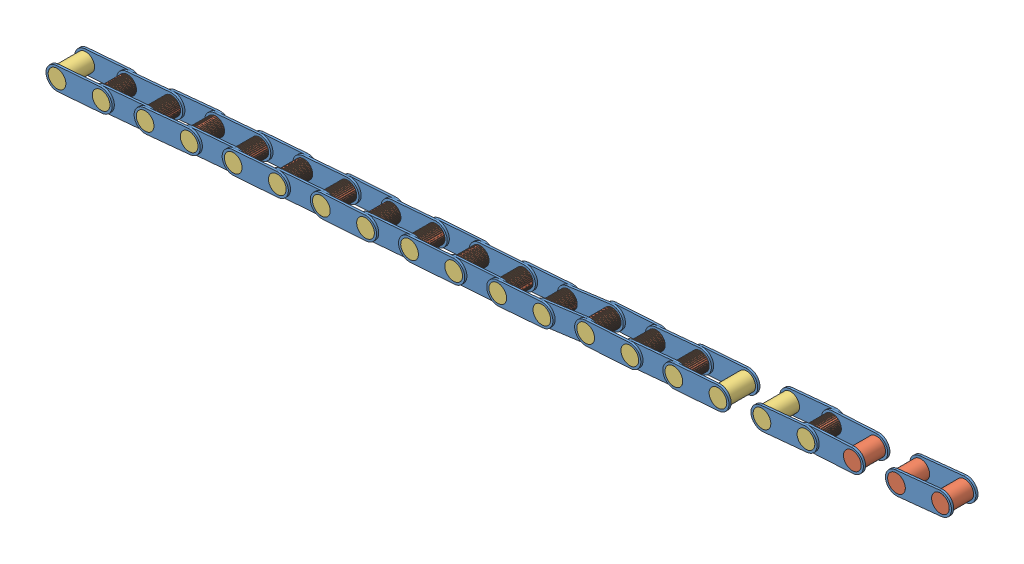
SolidWorks assembly PartialChain, configuration Default. Lengths in mm.
Overall size (522.65 65.14 17.78).
90 component instances, 3 part files, 30 mates.
Components (placement in the parent):
- SmallLinkageChain-1: SmallLinkageChain [Default] at (499.099 100.5897 2199.1354) x (0.994757 0.10227 0) z (0 0 1) size (38.1 12.7 15.24)
  - LinkagePart-1: LinkagePart [Default] at (73.4379 54.8795 -38.979) size (38.1 12.7 1.27)
  - SmallLinkCylinder-1: SmallLinkCylinder [Default] at (24.7536 -17.0726 -38.979) size (10.16 10.16 15.24)
  - SmallLinkCylinder-2: SmallLinkCylinder [Default] at (-0.6464 -17.0726 -38.979) size (10.16 10.16 15.24)
  - LinkagePart-2: LinkagePart [Default] at (73.4379 54.8795 -25.009) size (38.1 12.7 1.27)
- SmallLinkageChain-2: SmallLinkageChain [Default] at (448.5561 97.3025 2199.1354) x (0.998418 0.056236 0) z (0 0 1) size (38.1 12.7 15.24)
  - LinkagePart-1: LinkagePart [Default] at (73.4379 54.8795 -38.979) size (38.1 12.7 1.27)
  - SmallLinkCylinder-1: SmallLinkCylinder [Default] at (24.7536 -17.0726 -38.979) size (10.16 10.16 15.24)
  - SmallLinkCylinder-2: SmallLinkCylinder [Default] at (-0.6464 -17.0726 -38.979) size (10.16 10.16 15.24)
  - LinkagePart-2: LinkagePart [Default] at (73.4379 54.8795 -25.009) size (38.1 12.7 1.27)
- LargeLinkageChain-4: LargeLinkageChain [Default] at (437.9243 93.0349 2186.1263) x (0.952131 0.30569 0) z (0 0 1) size (39.94 20.59 17.78)
  - LargeLinkCylinder-3: LargeLinkCylinder [Default] at (9.0301 0.4096 -27.24) size (10.16 10.16 17.78)
  - LargeLinkCylinder-4: LargeLinkCylinder [Default] at (-22.7935 -2.2602 -27.24) x (0.146196 -0.989256 0) z (0 0 1) size (10.16 10.16 17.78)
  - LinkagePart-3: LinkagePart [Default] at (70.1186 44.4805 -10.73) x (0.976612 -0.215008 0) z (0 0 1) size (38.1 12.7 1.27)
  - LinkagePart-4: LinkagePart [Default] at (70.1186 44.4805 -27.24) x (0.976612 -0.215008 0) z (0 0 1) size (38.1 12.7 1.27)
- LargeLinkageChain-5: LargeLinkageChain [Default] at (387.3358 88.2933 2186.1263) x (0.957464 0.288553 0) z (0 0 1) size (39.94 20.59 17.78)
  - LargeLinkCylinder-3: LargeLinkCylinder [Default] at (9.0301 0.4096 -27.24) size (10.16 10.16 17.78)
  - LargeLinkCylinder-4: LargeLinkCylinder [Default] at (-22.7935 -2.2602 -27.24) x (0.146196 -0.989256 0) z (0 0 1) size (10.16 10.16 17.78)
  - LinkagePart-3: LinkagePart [Default] at (70.1186 44.4805 -10.73) x (0.976612 -0.215008 0) z (0 0 1) size (38.1 12.7 1.27)
  - LinkagePart-4: LinkagePart [Default] at (70.1186 44.4805 -27.24) x (0.976612 -0.215008 0) z (0 0 1) size (38.1 12.7 1.27)
- SmallLinkageChain-4: SmallLinkageChain [Default] at (347.2261 88.6639 2199.1354) x (0.995906 0.0904 0) z (0 0 1) size (38.1 12.7 15.24)
  - LinkagePart-1: LinkagePart [Default] at (73.4379 54.8795 -38.979) size (38.1 12.7 1.27)
  - SmallLinkCylinder-1: SmallLinkCylinder [Default] at (24.7536 -17.0726 -38.979) size (10.16 10.16 15.24)
  - SmallLinkCylinder-2: SmallLinkCylinder [Default] at (-0.6464 -17.0726 -38.979) size (10.16 10.16 15.24)
  - LinkagePart-2: LinkagePart [Default] at (73.4379 54.8795 -25.009) size (38.1 12.7 1.27)
- LargeLinkageChain-6: LargeLinkageChain [Default] at (336.7039 84.078 2186.1263) x (0.961656 0.274257 0) z (0 0 1) size (39.94 20.59 17.78)
  - LargeLinkCylinder-3: LargeLinkCylinder [Default] at (9.0301 0.4096 -27.24) size (10.16 10.16 17.78)
  - LargeLinkCylinder-4: LargeLinkCylinder [Default] at (-22.7935 -2.2602 -27.24) x (0.146196 -0.989256 0) z (0 0 1) size (10.16 10.16 17.78)
  - LinkagePart-3: LinkagePart [Default] at (70.1186 44.4805 -10.73) x (0.976612 -0.215008 0) z (0 0 1) size (38.1 12.7 1.27)
  - LinkagePart-4: LinkagePart [Default] at (70.1186 44.4805 -27.24) x (0.976612 -0.215008 0) z (0 0 1) size (38.1 12.7 1.27)
- SmallLinkageChain-5: SmallLinkageChain [Default] at (296.5195 84.1445 2199.1354) x (0.991043 0.13354 0) z (0 0 1) size (38.1 12.7 15.24)
  - LinkagePart-1: LinkagePart [Default] at (73.4379 54.8795 -38.979) size (38.1 12.7 1.27)
  - SmallLinkCylinder-1: SmallLinkCylinder [Default] at (24.7536 -17.0726 -38.979) size (10.16 10.16 15.24)
  - SmallLinkCylinder-2: SmallLinkCylinder [Default] at (-0.6464 -17.0726 -38.979) size (10.16 10.16 15.24)
  - LinkagePart-2: LinkagePart [Default] at (73.4379 54.8795 -25.009) size (38.1 12.7 1.27)
- LargeLinkageChain-7: LargeLinkageChain [Default] at (286.189 79.1239 2186.1263) x (0.957048 0.289931 0) z (0 0 1) size (39.94 20.59 17.78)
  - LargeLinkCylinder-3: LargeLinkCylinder [Default] at (9.0301 0.4096 -27.24) size (10.16 10.16 17.78)
  - LargeLinkCylinder-4: LargeLinkCylinder [Default] at (-22.7935 -2.2602 -27.24) x (0.146196 -0.989256 0) z (0 0 1) size (10.16 10.16 17.78)
  - LinkagePart-3: LinkagePart [Default] at (70.1186 44.4805 -10.73) x (0.976612 -0.215008 0) z (0 0 1) size (38.1 12.7 1.27)
  - LinkagePart-4: LinkagePart [Default] at (70.1186 44.4805 -27.24) x (0.976612 -0.215008 0) z (0 0 1) size (38.1 12.7 1.27)
- SmallLinkageChain-6: SmallLinkageChain [Default] at (246.1236 79.8127 2199.1354) x (0.997717 0.067536 0) z (0 0 1) size (38.1 12.7 15.24)
  - LinkagePart-1: LinkagePart [Default] at (73.4379 54.8795 -38.979) size (38.1 12.7 1.27)
  - SmallLinkCylinder-1: SmallLinkCylinder [Default] at (24.7536 -17.0726 -38.979) size (10.16 10.16 15.24)
  - SmallLinkCylinder-2: SmallLinkCylinder [Default] at (-0.6464 -17.0726 -38.979) size (10.16 10.16 15.24)
  - LinkagePart-2: LinkagePart [Default] at (73.4379 54.8795 -25.009) size (38.1 12.7 1.27)
- LargeLinkageChain-8: LargeLinkageChain [Default] at (235.5191 75.4473 2186.1263) x (0.958889 0.283783 0) z (0 0 1) size (39.94 20.59 17.78)
  - LargeLinkCylinder-3: LargeLinkCylinder [Default] at (9.0301 0.4096 -27.24) size (10.16 10.16 17.78)
  - LargeLinkCylinder-4: LargeLinkCylinder [Default] at (-22.7935 -2.2602 -27.24) x (0.146196 -0.989256 0) z (0 0 1) size (10.16 10.16 17.78)
  - LinkagePart-3: LinkagePart [Default] at (70.1186 44.4805 -10.73) x (0.976612 -0.215008 0) z (0 0 1) size (38.1 12.7 1.27)
  - LinkagePart-4: LinkagePart [Default] at (70.1186 44.4805 -27.24) x (0.976612 -0.215008 0) z (0 0 1) size (38.1 12.7 1.27)
- SmallLinkageChain-7: SmallLinkageChain [Default] at (195.4189 76.0792 2199.1354) x (0.996677 0.081461 0) z (0 0 1) size (38.1 12.7 15.24)
  - LinkagePart-1: LinkagePart [Default] at (73.4379 54.8795 -38.979) size (38.1 12.7 1.27)
  - SmallLinkCylinder-1: SmallLinkCylinder [Default] at (24.7536 -17.0726 -38.979) size (10.16 10.16 15.24)
  - SmallLinkCylinder-2: SmallLinkCylinder [Default] at (-0.6464 -17.0726 -38.979) size (10.16 10.16 15.24)
  - LinkagePart-2: LinkagePart [Default] at (73.4379 54.8795 -25.009) size (38.1 12.7 1.27)
- LargeLinkageChain-9: LargeLinkageChain [Default] at (184.8635 71.5797 2186.1263) x (0.960726 0.277497 0) z (0 0 1) size (39.94 20.59 17.78)
  - LargeLinkCylinder-3: LargeLinkCylinder [Default] at (9.0301 0.4096 -27.24) size (10.16 10.16 17.78)
  - LargeLinkCylinder-4: LargeLinkCylinder [Default] at (-22.7935 -2.2602 -27.24) x (0.146196 -0.989256 0) z (0 0 1) size (10.16 10.16 17.78)
  - LinkagePart-3: LinkagePart [Default] at (70.1186 44.4805 -10.73) x (0.976612 -0.215008 0) z (0 0 1) size (38.1 12.7 1.27)
  - LinkagePart-4: LinkagePart [Default] at (70.1186 44.4805 -27.24) x (0.976612 -0.215008 0) z (0 0 1) size (38.1 12.7 1.27)
- SmallLinkageChain-8: SmallLinkageChain [Default] at (144.7619 72.4221 2199.1354) x (0.996929 0.078304 0) z (0 0 1) size (38.1 12.7 15.24)
  - LinkagePart-1: LinkagePart [Default] at (73.4379 54.8795 -38.979) size (38.1 12.7 1.27)
  - SmallLinkCylinder-1: SmallLinkCylinder [Default] at (24.7536 -17.0726 -38.979) size (10.16 10.16 15.24)
  - SmallLinkCylinder-2: SmallLinkCylinder [Default] at (-0.6464 -17.0726 -38.979) size (10.16 10.16 15.24)
  - LinkagePart-2: LinkagePart [Default] at (73.4379 54.8795 -25.009) size (38.1 12.7 1.27)
- LargeLinkageChain-10: LargeLinkageChain [Default] at (134.2007 67.9472 2186.1263) x (0.957853 0.28726 0) z (0 0 1) size (39.94 20.59 17.78)
  - LargeLinkCylinder-3: LargeLinkCylinder [Default] at (9.0301 0.4096 -27.24) size (10.16 10.16 17.78)
  - LargeLinkCylinder-4: LargeLinkCylinder [Default] at (-22.7935 -2.2602 -27.24) x (0.146196 -0.989256 0) z (0 0 1) size (10.16 10.16 17.78)
  - LinkagePart-3: LinkagePart [Default] at (70.1186 44.4805 -10.73) x (0.976612 -0.215008 0) z (0 0 1) size (38.1 12.7 1.27)
  - LinkagePart-4: LinkagePart [Default] at (70.1186 44.4805 -27.24) x (0.976612 -0.215008 0) z (0 0 1) size (38.1 12.7 1.27)
- SmallLinkageChain-9: SmallLinkageChain [Default] at (94.1024 68.4688 2199.1354) x (0.996566 0.082803 0) z (0 0 1) size (38.1 12.7 15.24)
  - LinkagePart-1: LinkagePart [Default] at (73.4379 54.8795 -38.979) size (38.1 12.7 1.27)
  - SmallLinkCylinder-1: SmallLinkCylinder [Default] at (24.7536 -17.0726 -38.979) size (10.16 10.16 15.24)
  - SmallLinkCylinder-2: SmallLinkCylinder [Default] at (-0.6464 -17.0726 -38.979) size (10.16 10.16 15.24)
  - LinkagePart-2: LinkagePart [Default] at (73.4379 54.8795 -25.009) size (38.1 12.7 1.27)
- LargeLinkageChain-11: LargeLinkageChain [Default] at (83.5721 63.9353 2186.1263) x (0.951507 0.307628 0) z (0 0 1) size (39.94 20.59 17.78)
  - LargeLinkCylinder-3: LargeLinkCylinder [Default] at (9.0301 0.4096 -27.24) size (10.16 10.16 17.78)
  - LargeLinkCylinder-4: LargeLinkCylinder [Default] at (-22.7935 -2.2602 -27.24) x (0.146196 -0.989256 0) z (0 0 1) size (10.16 10.16 17.78)
  - LinkagePart-3: LinkagePart [Default] at (70.1186 44.4805 -10.73) x (0.976612 -0.215008 0) z (0 0 1) size (38.1 12.7 1.27)
  - LinkagePart-4: LinkagePart [Default] at (70.1186 44.4805 -27.24) x (0.976612 -0.215008 0) z (0 0 1) size (38.1 12.7 1.27)
- SmallLinkageChain-10: SmallLinkageChain [Default] at (43.4973 63.8485 2199.1354) x (0.99611 0.088123 0) z (0 0 1) size (38.1 12.7 15.24)
  - LinkagePart-1: LinkagePart [Default] at (73.4379 54.8795 -38.979) size (38.1 12.7 1.27)
  - SmallLinkCylinder-1: SmallLinkCylinder [Default] at (24.7536 -17.0726 -38.979) size (10.16 10.16 15.24)
  - SmallLinkCylinder-2: SmallLinkCylinder [Default] at (-0.6464 -17.0726 -38.979) size (10.16 10.16 15.24)
  - LinkagePart-2: LinkagePart [Default] at (73.4379 54.8795 -25.009) size (38.1 12.7 1.27)
- LargeLinkageChain-12: LargeLinkageChain [Default] at (32.9766 59.274 2186.1263) x (0.956851 0.290578 0) z (0 0 1) size (39.94 20.59 17.78)
  - LargeLinkCylinder-3: LargeLinkCylinder [Default] at (9.0301 0.4096 -27.24) size (10.16 10.16 17.78)
  - LargeLinkCylinder-4: LargeLinkCylinder [Default] at (-22.7935 -2.2602 -27.24) x (0.146196 -0.989256 0) z (0 0 1) size (10.16 10.16 17.78)
  - LinkagePart-3: LinkagePart [Default] at (70.1186 44.4805 -10.73) x (0.976612 -0.215008 0) z (0 0 1) size (38.1 12.7 1.27)
  - LinkagePart-4: LinkagePart [Default] at (70.1186 44.4805 -27.24) x (0.976612 -0.215008 0) z (0 0 1) size (38.1 12.7 1.27)
Mates (geometry in assembly coordinates):
- Concentric5: concentric aligned: cylinder of SmallLinkageChain-2/SmallLinkCylinder-2 through (438.5711 93.6728 2175.3964) axis (0 0 -1) radius 5.08; cylinder of LargeLinkageChain-4/LargeLinkCylinder-3 through (438.5711 93.6728 2176.6664) axis (0 0 -1) radius 5.08
- Coincident8: coincident aligned: circle of SmallLinkageChain-2/SmallLinkCylinder-2; circle of LargeLinkageChain-4/LinkagePart-3
- Concentric8: concentric aligned: cylinder of LargeLinkageChain-5/LargeLinkCylinder-4 through (362.6673 86.9904 2176.6664) axis (0 0 -1) radius 5.08; cylinder of SmallLinkageChain-4/SmallLinkCylinder-1 through (362.6673 86.9904 2175.3964) axis (0 0 -1) radius 5.08
- Coincident12: coincident aligned: circle of LargeLinkageChain-5/LinkagePart-4; circle of SmallLinkageChain-4/SmallLinkCylinder-1
- Concentric9: concentric aligned: cylinder of SmallLinkageChain-4/SmallLinkCylinder-2 through (337.3713 84.6943 2175.3964) axis (0 0 -1) radius 5.08; cylinder of LargeLinkageChain-6/LargeLinkCylinder-3 through (337.3713 84.6943 2176.6664) axis (0 0 -1) radius 5.08
- Coincident13: coincident aligned: circle of SmallLinkageChain-4/SmallLinkCylinder-2; circle of LargeLinkageChain-6/LinkagePart-3
- Concentric10: concentric aligned: cylinder of LargeLinkageChain-6/LargeLinkCylinder-4 through (312.0188 83.1429 2176.6664) axis (0 0 -1) radius 5.08; cylinder of SmallLinkageChain-5/SmallLinkCylinder-1 through (312.0188 83.1429 2175.3964) axis (0 0 -1) radius 5.08
- Coincident14: coincident aligned: circle of LargeLinkageChain-6/LinkagePart-3; circle of SmallLinkageChain-5/SmallLinkCylinder-1
- Concentric11: concentric aligned: cylinder of SmallLinkageChain-5/SmallLinkCylinder-2 through (286.8463 79.751 2175.3964) axis (0 0 -1) radius 5.08; cylinder of LargeLinkageChain-7/LargeLinkCylinder-3 through (286.8463 79.751 2176.6664) axis (0 0 -1) radius 5.08
- Coincident15: coincident aligned: circle of SmallLinkageChain-5/SmallLinkCylinder-2; circle of LargeLinkageChain-7/LinkagePart-3
- Concentric12: concentric aligned: cylinder of LargeLinkageChain-7/LargeLinkCylinder-4 through (261.5224 77.7856 2176.6664) axis (0 0 -1) radius 5.08; cylinder of SmallLinkageChain-6/SmallLinkCylinder-1 through (261.5224 77.7856 2175.3964) axis (0 0 -1) radius 5.08
- Coincident16: coincident aligned: circle of LargeLinkageChain-7/LinkagePart-3; circle of SmallLinkageChain-6/LinkagePart-2
- Concentric13: concentric aligned: cylinder of SmallLinkageChain-6/SmallLinkCylinder-2 through (236.1804 76.0701 2175.3964) axis (0 0 -1) radius 5.08; cylinder of LargeLinkageChain-8/LargeLinkCylinder-3 through (236.1804 76.0701 2176.6664) axis (0 0 -1) radius 5.08
- Coincident17: coincident aligned: circle of SmallLinkageChain-6/LinkagePart-2; circle of LargeLinkageChain-8/LinkagePart-3
- Concentric14: concentric aligned: cylinder of LargeLinkageChain-8/LargeLinkCylinder-4 through (210.8445 74.2673 2176.6664) axis (0 0 -1) radius 5.08; cylinder of SmallLinkageChain-7/SmallLinkCylinder-1 through (210.8445 74.2673 2175.3964) axis (0 0 -1) radius 5.08
- Coincident18: coincident aligned: circle of LargeLinkageChain-8/LinkagePart-3; circle of SmallLinkageChain-7/LinkagePart-2
- Concentric15: concentric aligned: cylinder of SmallLinkageChain-7/SmallLinkCylinder-2 through (185.5289 72.1982 2175.3964) axis (0 0 -1) radius 5.08; cylinder of LargeLinkageChain-9/LargeLinkCylinder-3 through (185.5289 72.1982 2176.6664) axis (0 0 -1) radius 5.08
- Coincident19: coincident aligned: circle of SmallLinkageChain-7/SmallLinkCylinder-2; circle of LargeLinkageChain-9/LinkagePart-3
- Concentric16: concentric aligned: cylinder of LargeLinkageChain-9/LargeLinkCylinder-4 through (160.1817 70.5613 2176.6664) axis (0 0 -1) radius 5.08; cylinder of SmallLinkageChain-8/SmallLinkCylinder-1 through (160.1817 70.5613 2175.3964) axis (0 0 -1) radius 5.08
- Coincident21: coincident aligned: circle of LargeLinkageChain-9/LinkagePart-3; circle of SmallLinkageChain-8/SmallLinkCylinder-1
- Concentric18: concentric aligned: cylinder of SmallLinkageChain-8/SmallLinkCylinder-2 through (134.8597 68.5724 2175.3964) axis (0 0 -1) radius 5.08; cylinder of LargeLinkageChain-10/LargeLinkCylinder-3 through (134.8597 68.5724 2176.6664) axis (0 0 -1) radius 5.08
- Coincident22: coincident aligned: circle of SmallLinkageChain-8/SmallLinkCylinder-2; circle of LargeLinkageChain-10/LinkagePart-3
- Concentric19: concentric aligned: cylinder of LargeLinkageChain-10/LargeLinkCylinder-4 through (109.5304 66.6776 2176.6664) axis (0 0 -1) radius 5.08; cylinder of SmallLinkageChain-9/SmallLinkCylinder-1 through (109.5304 66.6776 2175.3964) axis (0 0 -1) radius 5.08
- Coincident23: coincident aligned: circle of LargeLinkageChain-10/LinkagePart-4; circle of SmallLinkageChain-9/SmallLinkCylinder-1
- Concentric20: concentric aligned: cylinder of SmallLinkageChain-9/SmallLinkCylinder-2 through (84.2177 64.5744 2175.3964) axis (0 0 -1) radius 5.08; cylinder of LargeLinkageChain-11/LargeLinkCylinder-3 through (84.2177 64.5744 2176.6664) axis (0 0 -1) radius 5.08
- Coincident24: coincident anti-aligned: plane of SmallLinkageChain-9/SmallLinkCylinder-2 through (84.2177 64.5744 2160.1564) normal (0 0 -1); circle of LargeLinkageChain-11/LinkagePart-4
- Concentric21: concentric aligned: cylinder of LargeLinkageChain-11/LargeLinkCylinder-4 through (58.9346 62.1398 2176.6664) axis (0 0 -1) radius 5.08; cylinder of SmallLinkageChain-10/SmallLinkCylinder-1 through (58.9346 62.1398 2175.3964) axis (0 0 -1) radius 5.08
- Coincident25: coincident aligned: circle of LargeLinkageChain-11/LinkagePart-3; circle of SmallLinkageChain-10/LinkagePart-2
- Concentric22: concentric aligned: cylinder of SmallLinkageChain-10/SmallLinkCylinder-2 through (33.6334 59.9015 2175.3964) axis (0 0 -1) radius 5.08; cylinder of LargeLinkageChain-12/LargeLinkCylinder-3 through (33.6334 59.9015 2176.6664) axis (0 0 -1) radius 5.08
- Coincident26: coincident aligned: circle of SmallLinkageChain-10/SmallLinkCylinder-2; circle of LargeLinkageChain-12/LinkagePart-3
